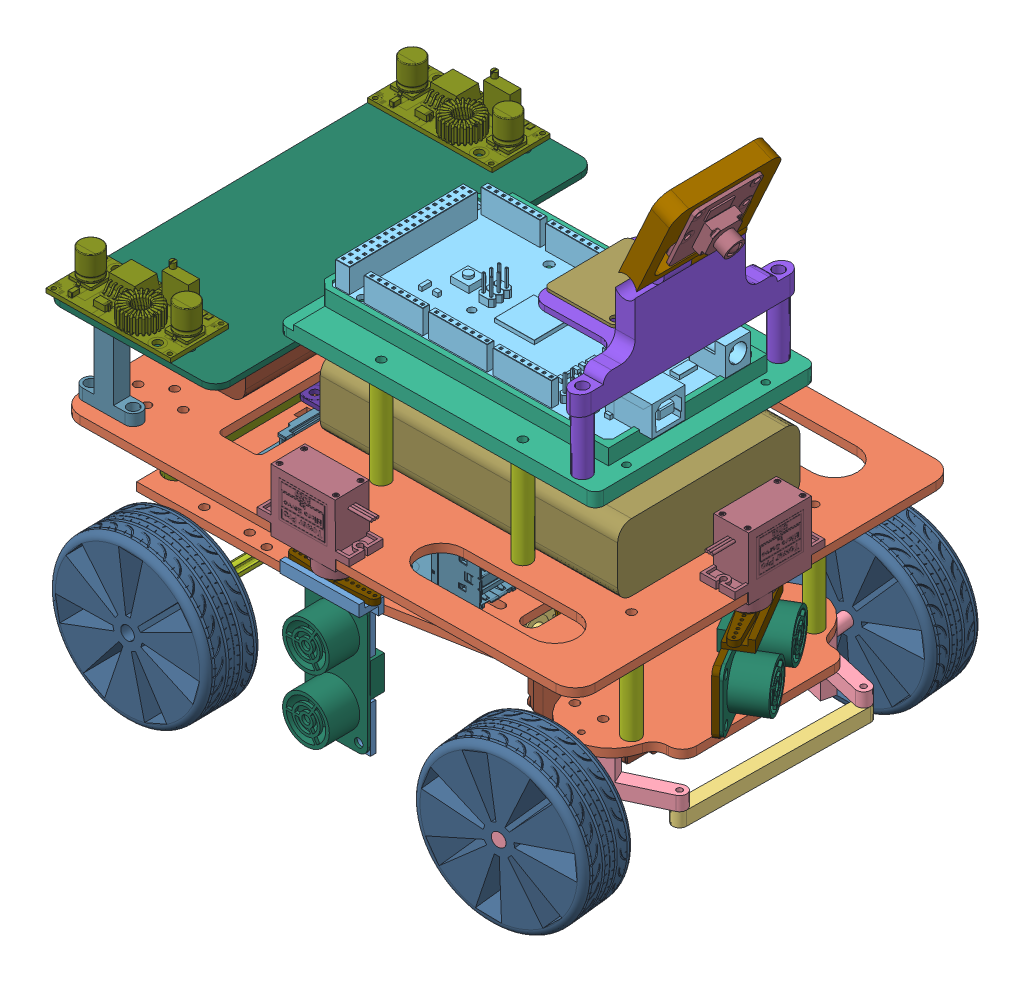
SolidWorks assembly Assem1, configuration Default. Lengths in mm.
Overall size (212.54 214.25 158.19).
63 component instances, 37 part files, 163 mates.
Components (placement in the parent):
- Lego Beam Fram 5x7 (64179)-2: Lego Beam Fram 5x7 (64179) [Default] at (1116.1167 -16.8 401.0707) x (0.999923 0 -0.012414) z (0 -1 0) size (56 40 8.03)
- chassis-2: chassis [Default] at (910.3673 -11.2 583.6389) x (-0.012414 0 -0.999923) z (-0.999923 0 0.012414) size (90 3 182)
- Core-DC-motor-jsumo-1: Core-DC-motor-jsumo [Default] at (985.0615 -28 582.7116) x (-0.012414 0 -0.999923) z (0.999923 0 -0.012414) size (15 12.1 46.7)
- Lego Beam Fram 5x7 (64179)-3: Lego Beam Fram 5x7 (64179) [Default] at (1120.5858 -32 761.0429) x (0.999923 0 -0.012414) z (0 1 0) size (56 40 8.03)
- (8258)_62821a-DkBluishGray v1-1: (8258)_62821a-DkBluishGray v1 [Default] at (938.2162 -28 571.2922) x (0.793634 -0.608316 -0.009853) z (-0.608269 -0.793695 0.007552) size (29.36 24.07 29.36)
- gear1-1: gear1 [Default] at (964.4047 -29.2721 521.6633) x (-0.138574 -0.225747 -0.96428) z (0.963872 -0.254394 -0.078959) size (6.66 13 13.05)
- gear1-2: gear1 [Default] at (885.5141 2.2697 557.1096) x (-0.878105 0.439182 0.189871) z (-0.360358 -0.345987 -0.866276) size (6.66 13 13.05)
- gear1-3: gear1 [Default] at (941.8438 -1.3082 642.1527) x (-0.230121 -0.091434 0.968857) z (-0.106516 0.991961 0.068315) size (6.66 13 13.05)
- 32269 Technic Gear 20 Tooth Double Bevel-1: 32269 Technic Gear 20 Tooth Double Bevel [Default] at (954.4314 -28 583.0919) x (-0.999923 0 0.012414) z (0.012093 0.225803 0.974098) size (7.95 21.33 21.33)
- 44294 Black Technic Axle 7 v1-1: 44294 Black Technic Axle 7 v1 [Default] at (938.3006 -28 578.0917) x (-0.012414 0 -0.999923) z (0.983452 -0.180757 -0.012209) size (56 4.8 4.8)
- 44294 Black Technic Axle 7 v1-2: 44294 Black Technic Axle 7 v1 [Default] at (939.0951 -28 642.0868) x (-0.012414 0 -0.999923) z (0.983452 -0.180757 -0.012209) size (56 4.8 4.8)
- dc holder-1: dc holder [Default] at (989.0612 -25.625 582.6619) x (0.012414 0 0.999923) z (0.999923 0 -0.012414) size (45 10.75 11)
- dc holder2-1: dc holder2 [Default] at (1006.3294 -18.0698 569.9466) x (-0.999923 0 0.012414) z (0.012414 0 0.999923) size (25 22.25 45)
- 56mm Wheel Normal Tread v1-1: 56mm Wheel Normal Tread v1 [Default] at (986.4091 9.1172 655.7005) x (-0.618573 0.78569 0.00768) z (-0.012414 0 -0.999923) size (56 56 20.01)
- 56mm Wheel Normal Tread v1-2: 56mm Wheel Normal Tread v1 [Default] at (952.6765 30.0378 510.108) x (0.967223 -0.253645 -0.012008) z (0.012414 0 0.999923) size (56 56 20.01)
- Tower Pro MG-995, Analog Servo-1: Tower Pro MG-995, Analog Servo [Default] at (1054.3587 -24.1 582.0513) x (0 -1 0) z (0.012414 0 0.999923) size (19.81 47.29 67)
- power bank-1: power bank [Default] at (1067.6573 50.8 613.0128) x (-0.999923 0 0.012414) z (0 -1 0) size (105 66 24)
- servo-1: servo [Default] at (1008.363 45.1 651.1539) x (-0.999923 0 0.012414) z (0.012414 -0.002078 0.999921) size (35.6 29.7 12.5)
- servo-2: servo [Default] at (1006.8105 45.1 526.1036) x (-0.999923 0 0.012414) z (0.012414 -0.002078 0.999921) size (35.6 29.7 12.5)
- Raspberry Pi 4 Model B-1: Raspberry Pi 4 Model B [Default] at (970.8626 -7.4 582.8879) x (0.999923 0 -0.012414) z (0.012414 0 0.999923) size (88.99 19.91 58.4)
- URM09 ultrasonic sensor-1: URM09 ultrasonic sensor [Default] at (910.369 4.65 583.7739) x (-0.012414 0 -0.999923) z (0 1 0) size (47 17.1 22)
- wall-1: wall [Default] at (918.4819 8.2872 592.8181) x (-0.012414 0 -0.999923) z (-0.999923 0 0.012414) size (70 35 8)
- ServoHat for Raspberry-1: ServoHat for Raspberry [Default] at (960.6015 3.9 569.9742) x (-0.999923 0 0.012414) z (-0.012414 0 -0.999923) size (65 18.5 30)
- Servo Medium Horn-1: Servo Medium Horn [Default] at (1002.1364 18.6128 645.0257) x (-0.999923 0 0.012414) z (0.012414 -0.002078 0.999921) size (31.17 4.71 6.86)
- Servo Medium Horn-2: Servo Medium Horn [Default] at (1000.5839 18.6128 519.9753) x (-0.510712 0.0018 -0.85975) z (-0.859752 -0.001039 0.510711) size (31.17 4.71 6.86)
- URM09 ultrasonic sensor-2: URM09 ultrasonic sensor [Default] at (1002.1182 -12.2692 643.5316) x (0.000026 0.999998 0.002078) z (0.999923 0 -0.012414) size (47 17.1 22)
- servotoultra-1: servotoultra [Default] at (987.9963 9.664 633.7986) x (-0.012414 0.002078 -0.999921) z (0.999923 0 -0.012414) size (9 52.1 28)
- layer2-2: layer2 [Default] at (996.8416 23.8 -431.3964) x (-0.999923 0 0.012414) z (-0.012414 0 -0.999923) size (182 3 137.36)
- servotoultra-3: servotoultra [Default] at (997.947 9.6033 537.8067) x (-0.859752 -0.001039 0.510711) z (-0.510712 0.0018 -0.85975) size (9 52.1 28)
- URM09 ultrasonic sensor-4: URM09 ultrasonic sensor [Default] at (999.3537 -12.2736 520.6414) x (0.000026 0.999998 0.002078) z (-0.510712 0.0018 -0.85975) size (47 17.1 22)
- URM09 ultrasonic sensor-5: URM09 ultrasonic sensor [Default] at (1084.9092 1.2406 582.1947) x (0.510712 0 0.859752) z (0 1 0) size (47 17.1 22)
- middle-1: middle [Default] at (1091.7997 -32.7 611.5252) x (-0.012361 0 0.999924) z (-0.999924 0 -0.012361) size (70 5 5)
- side-1: side [Default] at (1092.6031 -14.2 546.5301) x (-0.97527 0 -0.221017) z (-0.221017 0 0.97527) size (41.48 22 36.07)
- side-2: side [Default] at (1091.7997 -36.2 611.5252) x (-0.906304 0 0.422627) z (-0.422627 0 -0.906304) size (41.48 22 36.07)
- 56mm Wheel Normal Tread v1-3: 56mm Wheel Normal Tread v1 [Default] at (1103.2585 26.1421 653.3939) x (-0.850647 0.51747 0.092869) z (-0.108529 0 -0.994093) size (56 56 20.01)
- 56mm Wheel Normal Tread v1-4: 56mm Wheel Normal Tread v1 [Default] at (1045.8916 31.9534 508.3395) x (0.947336 0.304362 -0.099589) z (0.104549 0 0.99452) size (56 56 20.01)
- ArduinoMega-1: ArduinoMega [Default] at (1012.1453 68.451 582.3772) x (0.999923 0 -0.012414) z (0 -1 0) size (107.95 53.42 12.95)
- Arduino Mega Case1-1: Arduino Mega Case1 [Default] at (1015.3496 61.8 581.9138) x (-0.999923 0 0.012414) z (-0.012414 0 -0.999923) size (112.02 10.5 80)
- hexa-1: hexa [Default] at (1040.9219 26.8 546.5191) size (6 35 6)
- hexa-2: hexa [Default] at (1041.8033 26.8 617.5099) size (6 35 6)
- hexa-3: hexa [Default] at (991.8071 26.8 618.1306) size (6 35 6)
- hexa-4: hexa [Default] at (990.9258 26.8 547.1398) size (6 35 6)
- cameraholder-1: cameraholder [Default] at (1055.4272 83.8 580.0213) x (0.012414 0 0.999923) z (-0.999923 0 0.012414) size (79.94 53.8 37.5)
- cameraholder2-1: cameraholder2 [Default] at (1073.1754 128.8363 583.8508) x (0.012414 0 0.999923) z (-0.90993 0.414608 0.011297) size (40 38.8 8)
- DRV8871_module-2: DRV8871_module [Default] at (1041.238 -10.45 567.173) x (-0.012414 0 -0.999923) z (0 1 0) size (20.32 24.13 5.45)
- battery-2: battery [Default] at (925.4133 45.3 592.7888) x (-0.012414 0 -0.999923) z (0 -1 0) size (73 34 18.5)
- bno086-1: bno086 [Default] at (1041.7556 94.8 583.0556) x (-0.999923 0 0.012414) z (0.012414 0 0.999923) size (25.4 1 30.48)
- Pi camera module3-1: Pi camera module3 [Default] at (1075.0098 130.2224 581.5987) x (-0.012414 0 -0.999923) z (0.414576 0.91 -0.005147) size (25 12.5 23.86)
- powerboardholder-1: powerboardholder [Default] at (921.1525 26.8 522.8203) x (0.999923 0 -0.012414) z (0.012414 0 0.999923) size (21 30 6)
- powerboardholder-2: powerboardholder [Default] at (922.659 26.8 644.171) x (0.999923 0 -0.012414) z (0.012414 0 0.999923) size (21 30 6)
- powerboardholder2-1: powerboardholder2 [Default] at (912.0463 56.8 1334.6568) x (0.012414 0 0.999923) z (-0.999923 0 0.012414) size (137.36 2 60)
- XL4005_MODELO_3D_1-3: XL4005_MODELO_3D_1 [Default] at (927.1873 15.55 646.6872) x (0.999923 0 -0.012414) z (0 1 0) size (44.01 21.69 13.13)
- XL4005_MODELO_3D_1-4: XL4005_MODELO_3D_1 [Default] at (925.7428 15.55 530.3361) x (0.999923 0 -0.012414) z (0 1 0) size (44.01 21.69 13.13)
- hexaforraspberry-1: hexaforraspberry [Default] at (990.1653 -11.2 607.1501) size (6 3 6)
- hexaforraspberry-2: hexaforraspberry [Default] at (989.557 -11.2 558.1539) size (6 3 6)
- hexaforraspberry-3: hexaforraspberry [Default] at (931.5615 -11.2 558.8739) size (6 3 6)
- hexaforraspberry-4: hexaforraspberry [Default] at (932.1698 -11.2 607.8701) size (6 3 6)
- hexa-5: hexa [Default] at (1076.9448 -11.2 548.5683) size (6 35 6)
- hexa-6: hexa [Default] at (1077.6773 -11.2 614.5643) size (6 35 6)
- servotoultra - Copy-1: servotoultra - Copy [Default] at (1083.502 9.6531 599.3144) x (-0.859752 0 0.510712) z (-0.510712 0 -0.859752) size (9 26.1 47)
- servo-3: servo [Default] at (1080.1302 45.1256 587.6518) x (-0.012414 0 -0.999923) z (-0.999923 0 0.012414) size (35.6 29.7 12.5)
- Servo Medium Horn-3: Servo Medium Horn [Default] at (1086.2034 18.6256 581.4259) x (0.50278 0 0.864414) z (0.864414 0 -0.50278) size (31.17 4.71 6.86)
- additional-1: additional [Default] at (938.3651 -17.2 583.2913) x (-0.999923 0 0.012414) z (-0.012414 0 -0.999923) size (56 3 40)
Mates (geometry in assembly coordinates):
- Parallel3: parallel anti-aligned: plane of Lego Beam Fram 5x7 (64179)-2 through (910.3673 -17.2 583.6389) normal (0 1 0); plane of chassis-2 through (1048.4263 -14.2 616.9276) normal (0 -1 0)
- Distance2: distance = 21 mm aligned: plane of Lego Beam Fram 5x7 (64179)-2 through (962.115 -20.8 562.9949) normal (-0.012414 0 -0.999923); plane of chassis-2 through (909.8583 -14.2 542.6421) normal (-0.012414 0 -0.999923)
- Coincident8: coincident aligned: plane of Lego Beam Fram 5x7 (64179)-2 through (910.3673 -17.9 583.6389) normal (-0.999923 0 0.012414); plane of chassis-2 through (910.8763 -14.2 624.6357) normal (-0.999923 0 0.012414)
- Distance120: distance = 3 mm anti-aligned: plane of Lego Beam Fram 5x7 (64179)-2 through (910.3673 -17.2 583.6389) normal (0 1 0); plane of chassis-2 through (1048.4263 -14.2 616.9276) normal (0 -1 0)
- Coincident10: coincident anti-aligned: plane of Lego Beam Fram 5x7 (64179)-2 through (918.3667 -24.4 583.5396) normal (0 -1 0); plane of Lego Beam Fram 5x7 (64179)-3 through (918.3667 -24.4 583.5396) normal (0 1 0)
- Coincident11: coincident aligned: plane of Lego Beam Fram 5x7 (64179)-2 through (962.115 -20.8 562.9949) normal (-0.012414 0 -0.999923); plane of Lego Beam Fram 5x7 (64179)-3 through (962.115 -28 562.9949) normal (-0.012414 0 -0.999923)
- Concentric1: concentric aligned: cylinder of Lego Beam Fram 5x7 (64179)-2 through (914.1684 -20.8 567.5905) axis (0 -1 0) radius 2.4; cylinder of Lego Beam Fram 5x7 (64179)-3 through (914.1684 -28 567.5905) axis (0 -1 0) radius 2.4
- Parallel4: parallel anti-aligned: plane of chassis-2 through (1048.4263 -14.2 616.9276) normal (0 -1 0); plane of Core-DC-motor-jsumo-1 through (985.1422 -21.95 589.2111) normal (0 1 0)
- Concentric3: concentric aligned: cylinder of (8258)_62821a-DkBluishGray v1-1 through (938.2584 -28 574.692) axis (0.012414 0 0.999923) radius 2.4; cylinder of gear1-1 through (938.2584 -28 574.692) axis (0.012414 0 0.999923) radius 3.6
- Coincident13: coincident anti-aligned: plane of (8258)_62821a-DkBluishGray v1-1 through (936.3611 -26.54 575.3156) normal (0.012414 0 0.999923); plane of gear1-1 through (936.5286 -34.1597 575.3135) normal (-0.012414 0 -0.999923)
- Coincident15: coincident anti-aligned: plane of (8258)_62821a-DkBluishGray v1-1 through (928.8754 -27.1019 575.4085) normal (0.793634 -0.608316 -0.009853); plane of gear1-2 through (929.5081 -26.4257 584.6168) normal (-0.793634 0.608316 0.009853)
- Concentric5: concentric aligned: cylinder of (8258)_62821a-DkBluishGray v1-1 through (932.0012 -23.1335 582.1702) axis (0.793634 -0.608316 -0.009853) radius 1.2; cylinder of gear1-2 through (932.4774 -23.4985 582.1643) axis (0.793634 -0.608316 -0.009853) radius 3.6
- Coincident16: coincident anti-aligned: plane of (8258)_62821a-DkBluishGray v1-1 through (930.4983 -21.9168 588.9894) normal (-0.012414 0 -0.999923); plane of gear1-3 through (932.085 -28.7973 588.9697) normal (0.012414 0 0.999923)
- Concentric6: concentric anti-aligned: cylinder of (8258)_62821a-DkBluishGray v1-1 through (938.462 -28 591.0907) axis (0.012414 0 0.999923) radius 2.4; cylinder of gear1-3 through (938.4421 -28 589.4908) axis (-0.012414 0 -0.999923) radius 3.6
- Coincident18: coincident anti-aligned: plane of Lego Beam Fram 5x7 (64179)-3 through (914.218 -28 571.5902) normal (0.012414 0 0.999923); plane of (8258)_62821a-DkBluishGray v1-1 through (926.7879 -19.2402 571.4341) normal (-0.012414 0 -0.999923)
- Concentric7: concentric anti-aligned: cylinder of Lego Beam Fram 5x7 (64179)-3 through (938.1665 -28 567.2925) axis (-0.012414 0 -0.999923) radius 2.4; cylinder of (8258)_62821a-DkBluishGray v1-1 through (938.2584 -28 574.692) axis (0.012414 0 0.999923) radius 2.4
- Concentric10: concentric anti-aligned: cylinder of Core-DC-motor-jsumo-1 through (973.8624 -28 582.8506) axis (-0.999923 0 0.012414) radius 1.5; cylinder of 32269 Technic Gear 20 Tooth Double Bevel-1 through (950.4583 -28 583.1412) axis (0.999923 0 -0.012414) radius 1.6
- Concentric11: concentric anti-aligned: cylinder of Core-DC-motor-jsumo-1 through (973.8624 -28 582.8506) axis (-0.999923 0 0.012414) radius 1.5; cylinder of Lego Beam Fram 5x7 (64179)-3 through (910.3673 -28 583.6389) axis (0.999923 0 -0.012414) radius 2.4
- Distance4: distance = 40 mm aligned: plane of 32269 Technic Gear 20 Tooth Double Bevel-1 through (958.3636 -28 583.043) normal (0.999923 0 -0.012414); plane of Lego Beam Fram 5x7 (64179)-3 through (918.3667 -31.6 583.5396) normal (0.999923 0 -0.012414)
- Concentric12: concentric anti-aligned: cylinder of Lego Beam Fram 5x7 (64179)-3 through (938.5638 -28 599.2901) axis (-0.012414 0 -0.999923) radius 2.4; cylinder of 44294 Black Technic Axle 7 v1-1 through (937.6054 -28 522.096) axis (0.012414 0 0.999923) radius 2.4
- Concentric14: concentric anti-aligned: cylinder of Lego Beam Fram 5x7 (64179)-3 through (938.1665 -28 567.2925) axis (-0.012414 0 -0.999923) radius 2.4; cylinder of 44294 Black Technic Axle 7 v1-2 through (938.3999 -28 586.0911) axis (0.012414 0 0.999923) radius 2.4
- Coincident26: coincident aligned: plane of gear1-3 through (938.3999 -28 586.0911) normal (-0.012414 0 -0.999923); plane of 44294 Black Technic Axle 7 v1-2 through (938.3999 -28 586.0911) normal (-0.012414 0 -0.999923)
- Coincident27: coincident aligned: plane of gear1-1 through (938.3006 -28 578.0917) normal (0.012414 0 0.999923); plane of 44294 Black Technic Axle 7 v1-1 through (938.3006 -28 578.0917) normal (0.012414 0 0.999923)
- Coincident29: coincident anti-aligned: plane of Core-DC-motor-jsumo-1 through (985.1422 -21.95 589.2111) normal (0 1 0); plane of dc holder-1 through (1004.9813 -21.95 588.9648) normal (0 -1 0)
- Parallel6: parallel anti-aligned: plane of Core-DC-motor-jsumo-1 through (962.3336 -29.049 580.6029) normal (0 -1 0); plane of 32269 Technic Gear 20 Tooth Double Bevel-1 through (950.4717 -29.1805 584.2211) normal (0 1 0)
- Concentric19: concentric anti-aligned: cylinder of Core-DC-motor-jsumo-1 through (985.0615 -28 582.7116) axis (0.999923 0 -0.012414) radius 7.5; cylinder of dc holder2-1 through (1036.7017 -28 582.0705) axis (-0.999923 0 0.012414) radius 7.75
- Concentric20: concentric anti-aligned: cylinder of Core-DC-motor-jsumo-1 through (985.0615 -28 582.7116) axis (0.999923 0 -0.012414) radius 7.5; cylinder of dc holder2-1 through (1036.7017 -28 582.0705) axis (-0.999923 0 0.012414) radius 7.75
- Concentric21: concentric aligned: cylinder of 44294 Black Technic Axle 7 v1-2 through (938.3999 -28 586.0911) axis (0.012414 0 0.999923) radius 2.4; cylinder of 56mm Wheel Normal Tread v1-1 through (939.0231 -28 636.2854) axis (0.012414 0 0.999923) radius 2.4
- Concentric22: concentric anti-aligned: cylinder of 44294 Black Technic Axle 7 v1-1 through (937.6054 -28 522.096) axis (0.012414 0 0.999923) radius 2.4; cylinder of 56mm Wheel Normal Tread v1-2 through (937.7072 -28 530.2972) axis (-0.012414 0 -0.999923) radius 2.4
- Distance7: distance = 12 mm anti-aligned: plane of 56mm Wheel Normal Tread v1-1 through (939.0231 -28 636.2872) normal (-0.012414 0 -0.999923); plane of chassis-2 through (910.8763 -14.2 624.6357) normal (0.012414 0 0.999923)
- Distance8: distance = 12 mm anti-aligned: plane of 56mm Wheel Normal Tread v1-2 through (937.7072 -28 530.2954) normal (0.012414 0 0.999923); plane of chassis-2 through (909.8583 -14.2 542.6421) normal (-0.012414 0 -0.999923)
- Coincident47: coincident anti-aligned: plane of chassis-2 through (1048.4263 -14.2 616.9276) normal (0 -1 0); plane of Tower Pro MG-995, Analog Servo-1 through (1054.1067 -14.2 561.7528) normal (0 1 0)
- Coincident109: coincident anti-aligned: plane of URM09 ultrasonic sensor-1 through (910.369 4.65 583.7739) normal (0.999923 0 -0.012414); plane of wall-1 through (910.4825 8.2872 592.9174) normal (-0.999923 0 0.012414)
- Coincident124: coincident anti-aligned: plane of Raspberry Pi 4 Model B-1 through (936.4154 -4.1 557.5435) normal (0 1 0); plane of ServoHat for Raspberry-1 through (960.6015 -4.1 569.9742) normal (0 -1 0)
- Coincident126: coincident aligned: plane of Raspberry Pi 4 Model B-1 through (953.3083 -4.1 556.0637) normal (-0.012414 0 -0.999923); plane of ServoHat for Raspberry-1 through (985.9258 -4.1 555.6588) normal (-0.012414 0 -0.999923)
- Coincident127: coincident aligned: plane of Raspberry Pi 4 Model B-1 through (985.9307 -4.1 556.0587) normal (0.999923 0 -0.012414); plane of ServoHat for Raspberry-1 through (985.9258 -4.1 555.6588) normal (0.999923 0 -0.012414)
- Distance61: distance = 144 mm aligned: plane of Tower Pro MG-995, Analog Servo-1 through (1054.3587 -24.1 582.0513) normal (-0.999923 0 0.012414); plane of chassis-2 through (910.8763 -14.2 624.6357) normal (-0.999923 0 0.012414)
- Distance62: distance = 9.5 mm aligned: plane of Tower Pro MG-995, Analog Servo-1 through (1054.6107 -14.2 602.3497) normal (0.012414 0 0.999923); plane of chassis-2 through (1027.7932 -14.2 612.1834) normal (0.012414 0 0.999923)
- Concentric34: concentric aligned: cylinder of servo-1 through (1002.1363 15.4128 645.0191) axis (0.000026 0.999998 0.002078) radius 0.8; circle of Servo Medium Horn-1
- Coincident134: coincident anti-aligned: plane of servo-1 through (1000.6865 18.6128 645.0437) normal (-0.000026 -0.999998 -0.002078); plane of Servo Medium Horn-1 through (1002.1364 18.6128 645.0257) normal (0.000026 0.999998 0.002078)
- Concentric35: concentric aligned: cylinder of servo-2 through (1000.5839 15.4128 519.9687) axis (0.000026 0.999998 0.002078) radius 0.8; cylinder of Servo Medium Horn-2 through (1000.5839 15.8128 519.9695) axis (0.000026 0.999998 0.002078) radius 2.345
- Coincident135: coincident anti-aligned: plane of servo-2 through (999.134 18.6128 519.9933) normal (-0.000026 -0.999998 -0.002078); plane of Servo Medium Horn-2 through (1000.5839 18.6128 519.9753) normal (0.000026 0.999998 0.002078)
- Concentric36: concentric anti-aligned: cylinder of Servo Medium Horn-1 through (1010.3137 16.3278 644.9194) axis (-0.000026 -0.999998 -0.002078) radius 0.515; cylinder of servotoultra-1 through (1010.3136 12.2278 644.9109) axis (0.000026 0.999998 0.002078) radius 1.5
- Concentric41: concentric anti-aligned: cylinder of Servo Medium Horn-1 through (993.959 16.3278 645.1225) axis (-0.000026 -0.999998 -0.002078) radius 0.515; cylinder of servotoultra-1 through (993.9592 12.2278 645.114) axis (0.000026 0.999998 0.002078) radius 1.5
- Coincident138: coincident anti-aligned: plane of Servo Medium Horn-1 through (1002.1363 14.2278 645.0166) normal (-0.000026 -0.999998 -0.002078); plane of servotoultra-1 through (1016.1799 14.2204 648.4125) normal (0.000026 0.999998 0.002078)
- Coincident150: coincident anti-aligned: plane of chassis-2 through (1048.4263 -11.2 616.9276) normal (0 1 0); plane of wall-1 through (910.8018 -11.2 618.6362) normal (0 -1 0)
- Coincident151: coincident anti-aligned: plane of wall-1 through (910.8018 23.8 618.6362) normal (0 1 0); plane of layer2-2 through (996.8416 23.8 -431.3964) normal (0 -1 0)
- Coincident152: coincident anti-aligned: plane of power bank-1 through (1067.6573 26.8 613.0128) normal (0 -1 0); plane of layer2-2 through (996.8416 26.8 -431.3964) normal (0 1 0)
- Distance68: distance = 20 mm aligned: plane of layer2-2 through (1093.2059 26.8 650.0543) normal (0.999923 0 -0.012414); plane of power bank-1 through (1071.9452 26.8 548.6304) normal (0.999923 0 -0.012414)
- Distance70: distance = 35.68 mm aligned: plane of layer2-2 through (1091.5007 26.8 512.7049) normal (-0.012414 0 -0.999923); plane of power bank-1 through (1071.9452 26.8 548.6304) normal (-0.012414 0 -0.999923)
- Coincident167: coincident anti-aligned: plane of servo-2 through (983.9591 26.8 514.0482) normal (0 -1 0); plane of layer2-2 through (996.8416 26.8 -431.3964) normal (0 1 0)
- Coincident172: coincident: line of servo-2 through (1000.5077 22.8256 513.8345) axis (-0.999923 0 0.012414); plane of layer2-2 through (1091.5007 26.8 512.7049) normal (-0.012414 0 -0.999923)
- Distance77: distance = 91 mm: line of assembly; plane of layer2-2 through (1093.2059 26.8 650.0543) normal (0.999923 0 -0.012414)
- Coincident174: coincident anti-aligned: plane of servo-1 through (1008.2098 26.8 638.8168) normal (0 -1 0); plane of layer2-2 through (996.8416 26.8 -431.3964) normal (0 1 0)
- Coincident175: coincident: line of servo-1 through (1002.2129 22.8 651.1839) axis (-0.999923 0 0.012414); plane of layer2-2 through (1093.2059 26.8 650.0543) normal (0.012414 0 0.999923)
- Distance78: distance = 91 mm: line of assembly; plane of layer2-2 through (1093.2059 26.8 650.0543) normal (0.999923 0 -0.012414)
- Parallel60: parallel anti-aligned: plane of chassis-2 through (910.8763 -14.2 624.6357) normal (-0.999923 0 0.012414); plane of servotoultra-1 through (1013.1179 9.2308 643.4398) normal (0.999923 0 -0.012414)
- Coincident183: coincident anti-aligned: plane of URM09 ultrasonic sensor-2 through (1002.1182 -12.2692 643.5316) normal (-0.012414 0.002078 -0.999921); plane of servotoultra-1 through (1016.1165 -35.7691 643.309) normal (0.012414 -0.002078 0.999921)
- Coincident192: coincident anti-aligned: plane of servotoultra-3 through (992.2031 -35.7484 508.5561) normal (0.859752 0.001039 -0.510711); plane of URM09 ultrasonic sensor-4 through (999.3537 -12.2736 520.6414) normal (-0.859752 -0.001039 0.510711)
- Coincident193: coincident aligned: plane of servotoultra-3 through (993.7364 9.2461 511.2289) normal (-0.510712 0.0018 -0.85975); plane of URM09 ultrasonic sensor-4 through (993.7353 -32.6038 511.1419) normal (-0.510712 0.0018 -0.85975)
- Coincident194: coincident aligned: plane of servotoultra-3 through (990.4836 -35.7504 509.5775) normal (-0.000026 -0.999998 -0.002078); plane of URM09 ultrasonic sensor-4 through (1003.3622 -35.7877 527.3416) normal (-0.000026 -0.999998 -0.002078)
- Concentric52: concentric anti-aligned: cylinder of Servo Medium Horn-2 through (1004.7605 16.3131 527.0016) axis (-0.000026 -0.999998 -0.002078) radius 0.515; cylinder of servotoultra-3 through (1004.7604 12.2131 526.9931) axis (0.000026 0.999998 0.002078) radius 1.5
- Concentric53: concentric anti-aligned: cylinder of Servo Medium Horn-2 through (996.4073 16.3425 512.9395) axis (-0.000026 -0.999998 -0.002078) radius 0.515; cylinder of servotoultra-3 through (996.4073 12.2425 512.9313) axis (0.000026 0.999998 0.002078) radius 1.5
- Coincident195: coincident anti-aligned: plane of Servo Medium Horn-2 through (1000.5838 14.2278 519.9662) normal (-0.000026 -0.999998 -0.002078); plane of servotoultra-3 through (996.5032 14.2567 506.1065) normal (0.000026 0.999998 0.002078)
- Angle4: planar angle = 2.094395 rad aligned: plane of chassis-2 through (910.8763 -14.2 624.6357) normal (-0.999923 0 0.012414); plane of servotoultra-3 through (997.947 9.6033 537.8067) normal (0.510712 -0.0018 0.85975)
- Parallel72: parallel anti-aligned: plane of chassis-2 through (1048.4263 -14.2 616.9276) normal (0 -1 0); plane of assembly through (0 0 0) normal (0 1 0)
- Tangent5: tangent: circle of 56mm Wheel Normal Tread v1-2; plane of assembly through (0 0 0) normal (0 1 0)
- Concentric54: concentric aligned: cylinder of chassis-2 through (1066.8462 -11.2 540.6931) axis (0 -1 0) radius 1; cylinder of side-1 through (1066.8462 -14.2 540.6931) axis (0 -1 0) radius 1
- Coincident205: coincident anti-aligned: plane of chassis-2 through (1048.4263 -14.2 616.9276) normal (0 -1 0); plane of side-1 through (1092.6031 -14.2 546.5301) normal (0 1 0)
- Concentric55: concentric anti-aligned: cylinder of chassis-2 through (1067.8642 -11.2 622.6868) axis (0 -1 0) radius 1; cylinder of side-2 through (1067.8642 -36.2 622.6868) axis (0 1 0) radius 1
- Coincident206: coincident anti-aligned: plane of chassis-2 through (1048.4263 -14.2 616.9276) normal (0 -1 0); plane of side-2 through (1091.7997 -14.2 611.5252) normal (0 1 0)
- Concentric56: concentric anti-aligned: cylinder of middle-1 through (1092.6031 -32.701 546.5301) axis (0 1 0) radius 1; cylinder of side-1 through (1092.6031 -14.2 546.5301) axis (0 -1 0) radius 1
- Concentric57: concentric aligned: cylinder of middle-1 through (1091.7997 -32.701 611.5252) axis (0 1 0) radius 1; cylinder of side-2 through (1091.7997 -36.2 611.5252) axis (0 1 0) radius 1
- Coincident207: coincident anti-aligned: plane of middle-1 through (1091.7997 -27.7 611.5252) normal (0 1 0); plane of side-1 through (1077.0637 -27.7 540.4452) normal (0 -1 0)
- Coincident208: coincident anti-aligned: plane of middle-1 through (1091.7997 -27.7 611.5252) normal (0 1 0); plane of side-2 through (1075.7891 -27.7 616.2328) normal (0 -1 0)
- Concentric61: concentric anti-aligned: cylinder of side-2 through (1072.3937 -25.2 656.7635) axis (-0.108529 0 -0.994093) radius 2.4; cylinder of 56mm Wheel Normal Tread v1-3 through (1070.2229 -25.2 636.8798) axis (0.108529 0 0.994093) radius 2.4
- Coincident220: coincident aligned: plane of side-2 through (1072.3937 -25.2 656.7635) normal (0.108529 0 0.994093); plane of 56mm Wheel Normal Tread v1-3 through (1072.3937 -25.2 656.7635) normal (0.108529 0 0.994093)
- Concentric62: concentric anti-aligned: cylinder of side-1 through (1064.0532 -25.2 506.4303) axis (0.104549 0 0.99452) radius 2.4; cylinder of 56mm Wheel Normal Tread v1-4 through (1066.1444 -25.2 526.3225) axis (-0.104549 0 -0.99452) radius 2.4
- Coincident221: coincident aligned: plane of side-1 through (1064.0532 -25.2 506.4303) normal (-0.104549 0 -0.99452); plane of 56mm Wheel Normal Tread v1-4 through (1064.0532 -25.2 506.4303) normal (-0.104549 0 -0.99452)
- Concentric63: concentric aligned: cylinder of ArduinoMega-1 through (973.9927 66.799 607.0209) axis (0 1 0) radius 1.5621; cylinder of Arduino Mega Case1-1 through (973.9927 58.8 607.0209) axis (0 1 0) radius 1.5621
- Concentric64: concentric aligned: cylinder of ArduinoMega-1 through (965.9002 66.799 558.7814) axis (0 1 0) radius 1.5621; cylinder of Arduino Mega Case1-1 through (965.9002 58.8 558.7814) axis (0 1 0) radius 1.5621
- Coincident223: coincident anti-aligned: plane of ArduinoMega-1 through (1062.6099 66.8 555.0406) normal (0 -1 0); plane of Arduino Mega Case1-1 through (1015.3496 66.8 581.9138) normal (0 1 0)
- Distance88: distance = 2 mm aligned: plane of chassis-2 through (1027.0483 -14.2 552.188) normal (-0.012414 0 -0.999923); plane of Raspberry Pi 4 Model B-1 through (928.0183 -6.6 555.4176) normal (-0.012414 0 -0.999923)
- Concentric72: concentric anti-aligned: cylinder of Arduino Mega Case1-1 through (1040.9219 60.7999 546.5191) axis (0 1 0) radius 1.5; cylinder of hexa-1 through (1040.9219 61.8 546.5191) axis (0 -1 0) radius 2
- Concentric73: concentric anti-aligned: cylinder of Arduino Mega Case1-1 through (990.9258 60.7999 547.1398) axis (0 1 0) radius 1.5; cylinder of hexa-4 through (990.9258 61.8 547.1398) axis (0 -1 0) radius 2
- Concentric74: concentric anti-aligned: cylinder of Arduino Mega Case1-1 through (1041.8033 60.7999 617.5099) axis (0 1 0) radius 1.5; cylinder of hexa-2 through (1041.8033 61.8 617.5099) axis (0 -1 0) radius 2
- Concentric75: concentric anti-aligned: cylinder of Arduino Mega Case1-1 through (991.8071 60.7999 618.1306) axis (0 1 0) radius 1.5; cylinder of hexa-3 through (991.8071 61.8 618.1306) axis (0 -1 0) radius 2
- Concentric82: concentric aligned: cylinder of Arduino Mega Case1-1 through (1061.9203 60.7999 546.2585) axis (0 1 0) radius 1.5; cylinder of cameraholder-1 through (1061.9203 63.8 546.2585) axis (0 1 0) radius 2
- Concentric87: concentric anti-aligned: cylinder of layer2-2 through (1040.9219 23.8 546.5191) axis (0 1 0) radius 1.5; cylinder of hexa-1 through (1040.9219 61.8 546.5191) axis (0 -1 0) radius 3
- Concentric89: concentric anti-aligned: cylinder of layer2-2 through (1041.8033 23.8 617.5099) axis (0 1 0) radius 1.5; cylinder of hexa-2 through (1041.8033 61.8 617.5099) axis (0 -1 0) radius 3
- Coincident245: coincident anti-aligned: plane of Arduino Mega Case1-1 through (1015.3496 63.8 581.9138) normal (0 1 0); plane of cameraholder-1 through (1062.8017 63.8 617.253) normal (0 -1 0)
- Concentric92: concentric aligned: cylinder of Arduino Mega Case1-1 through (1062.8017 60.7999 617.253) axis (0 1 0) radius 1.5; cylinder of cameraholder-1 through (1062.8017 63.8 617.253) axis (0 1 0) radius 3
- Coincident246: coincident anti-aligned: plane of layer2-2 through (996.8416 26.8 -431.3964) normal (0 1 0); plane of hexa-1 through (1040.9219 26.8 546.5191) normal (0 -1 0)
- Coincident248: coincident anti-aligned: plane of layer2-2 through (996.8416 26.8 -431.3964) normal (0 1 0); plane of battery-2 through (925.4133 26.8 592.7888) normal (0 -1 0)
- Coincident249: coincident aligned: plane of layer2-2 through (911.2199 26.8 652.3136) normal (-0.999923 0 0.012414); plane of battery-2 through (910.8204 26.8 620.1361) normal (-0.999923 0 0.012414)
- Distance100: distance = 32.18 mm aligned: plane of battery-2 through (943.9116 26.8 546.7196) normal (-0.012414 0 -0.999923); plane of layer2-2 through (1091.5007 26.8 512.7049) normal (-0.012414 0 -0.999923)
- Coincident260: coincident anti-aligned: plane of cameraholder-1 through (1029.1119 93.8 602.17) normal (0 1 0); plane of bno086-1 through (1041.7556 93.8 583.0556) normal (0 -1 0)
- Coincident263: coincident aligned: plane of cameraholder-1 through (1028.841 83.8 580.3514) normal (-0.999923 0 0.012414); plane of bno086-1 through (1029.0527 93.8 597.4004) normal (-0.999923 0 0.012414)
- Distance104: distance = 4.75 mm aligned: plane of cameraholder-1 through (1028.6153 93.8 562.1731) normal (-0.012414 0 -0.999923); plane of bno086-1 through (1054.0723 93.8 566.6074) normal (-0.012414 0 -0.999923)
- Coincident265: coincident anti-aligned: plane of cameraholder2-1 through (1073.1754 128.8363 583.8508) normal (0.90993 -0.414608 -0.011297); plane of Pi camera module3-1 through (1073.9907 130.6867 581.6113) normal (-0.90993 0.414608 0.011297)
- Distance106: distance = 7.5 mm aligned: plane of cameraholder2-1 through (1073.3557 146.7212 561.6177) normal (-0.012414 0 -0.999923); plane of Pi camera module3-1 through (1068.8892 119.8295 569.1737) normal (-0.012414 0 -0.999923)
- Distance105: distance = 2.5 mm aligned: plane of Pi camera module3-1 through (1079.0922 141.5439 594.049) normal (0.414576 0.91 -0.005147); plane of cameraholder2-1 through (1073.3557 146.7212 561.6177) normal (0.414576 0.91 -0.005147)
- Coincident268: coincident anti-aligned: plane of layer2-2 through (996.8416 26.8 -431.3964) normal (0 1 0); plane of powerboardholder-1 through (912.6138 26.8 522.9263) normal (0 -1 0)
- Tangent6: tangent aligned: plane of layer2-2 through (911.2199 26.8 652.3136) normal (-0.999923 0 0.012414); cylinder of powerboardholder-1 through (912.6138 56.8 522.9263) axis (0 -1 0) radius 3
- Coincident270: coincident anti-aligned: plane of layer2-2 through (996.8416 26.8 -431.3964) normal (0 1 0); plane of powerboardholder-2 through (914.1203 26.8 644.277) normal (0 -1 0)
- Tangent9: tangent aligned: plane of layer2-2 through (911.2199 26.8 652.3136) normal (-0.999923 0 0.012414); cylinder of powerboardholder-2 through (914.1203 56.8 644.277) axis (0 -1 0) radius 3
- Coincident273: coincident anti-aligned: plane of powerboardholder-1 through (912.6138 56.8 522.9263) normal (0 1 0); plane of powerboardholder2-1 through (961.154 56.8 646.6933) normal (0 -1 0)
- Distance111: distance = 5 mm aligned: plane of layer2-2 through (911.2199 26.8 652.3136) normal (-0.999923 0 0.012414); plane of powerboardholder2-1 through (906.1582 58.8 647.3761) normal (-0.999923 0 0.012414)
- Coincident286: coincident aligned: plane of URM09 ultrasonic sensor-2 through (994.2682 -35.7691 643.5802) normal (-0.000026 -0.999998 -0.002078); plane of servotoultra-1 through (1016.0917 -35.765 641.3092) normal (-0.000026 -0.999998 -0.002078)
- Coincident287: coincident aligned: plane of URM09 ultrasonic sensor-2 through (1013.1168 -32.6191 643.3528) normal (0.999923 0 -0.012414); plane of servotoultra-1 through (1013.1179 9.2308 643.4398) normal (0.999923 0 -0.012414)
- Coincident291: coincident aligned: plane of layer2-2 through (1091.5007 26.8 512.7049) normal (-0.012414 0 -0.999923); plane of powerboardholder2-1 through (959.5109 58.8 514.3435) normal (-0.012414 0 -0.999923)
- Coincident292: coincident anti-aligned: plane of powerboardholder2-1 through (961.154 58.8 646.6933) normal (0 1 0); plane of XL4005_MODELO_3D_1-4 through (926.6437 58.8 525.2524) normal (0 -1 0)
- Coincident293: coincident anti-aligned: plane of powerboardholder2-1 through (961.154 58.8 646.6933) normal (0 1 0); plane of XL4005_MODELO_3D_1-3 through (928.0882 58.8 641.6034) normal (0 -1 0)
- Coincident294: coincident aligned: plane of powerboardholder2-1 through (961.216 58.8 651.6929) normal (0.012414 0 0.999923); plane of XL4005_MODELO_3D_1-3 through (906.2203 60.3 652.3757) normal (0.012414 0 0.999923)
- Coincident295: coincident aligned: plane of powerboardholder2-1 through (906.1582 58.8 647.3761) normal (-0.999923 0 0.012414); plane of XL4005_MODELO_3D_1-3 through (905.9596 60.3 631.3773) normal (-0.999923 0 0.012414)
- Coincident296: coincident aligned: plane of powerboardholder2-1 through (959.5109 58.8 514.3435) normal (-0.012414 0 -0.999923); plane of XL4005_MODELO_3D_1-4 through (904.5151 60.3 515.0263) normal (-0.012414 0 -0.999923)
- Coincident297: coincident aligned: plane of powerboardholder2-1 through (906.1582 58.8 647.3761) normal (-0.999923 0 0.012414); plane of XL4005_MODELO_3D_1-4 through (904.5151 60.3 515.0263) normal (-0.999923 0 0.012414)
- Coincident298: coincident anti-aligned: plane of chassis-2 through (1048.4263 -11.2 616.9276) normal (0 1 0); plane of hexaforraspberry-3 through (931.5615 -11.2 558.8739) normal (0 -1 0)
- Coincident299: coincident anti-aligned: plane of chassis-2 through (1048.4263 -11.2 616.9276) normal (0 1 0); plane of hexaforraspberry-1 through (990.1653 -11.2 607.1501) normal (0 -1 0)
- Coincident300: coincident anti-aligned: plane of chassis-2 through (1048.4263 -11.2 616.9276) normal (0 1 0); plane of hexaforraspberry-4 through (932.1698 -11.2 607.8701) normal (0 -1 0)
- Coincident301: coincident anti-aligned: plane of chassis-2 through (1048.4263 -11.2 616.9276) normal (0 1 0); plane of hexaforraspberry-2 through (989.557 -11.2 558.1539) normal (0 -1 0)
- Concentric93: concentric anti-aligned: cylinder of Raspberry Pi 4 Model B-1 through (931.5615 -6.6 558.8739) axis (0 1 0) radius 1.35; cylinder of hexaforraspberry-3 through (931.5615 -8.2 558.8739) axis (0 -1 0) radius 2
- Coincident302: coincident anti-aligned: plane of Raspberry Pi 4 Model B-1 through (970.8626 -8.2 582.8879) normal (0 -1 0); plane of hexaforraspberry-3 through (931.5615 -8.2 558.8739) normal (0 1 0)
- Concentric94: concentric anti-aligned: cylinder of Raspberry Pi 4 Model B-1 through (989.557 -6.6 558.1539) axis (0 1 0) radius 1.35; cylinder of hexaforraspberry-2 through (989.557 -8.2 558.1539) axis (0 -1 0) radius 2
- Concentric95: concentric anti-aligned: cylinder of Raspberry Pi 4 Model B-1 through (932.1698 -6.6 607.8701) axis (0 1 0) radius 1.35; cylinder of hexaforraspberry-4 through (932.1698 -8.2 607.8701) axis (0 -1 0) radius 2
- Concentric96: concentric anti-aligned: cylinder of Raspberry Pi 4 Model B-1 through (990.1653 -6.6 607.1501) axis (0 1 0) radius 1.35; cylinder of hexaforraspberry-1 through (990.1653 -8.2 607.1501) axis (0 -1 0) radius 2
- Distance117: distance = 10 mm anti-aligned: plane of Raspberry Pi 4 Model B-1 through (928.0183 -6.6 555.4176) normal (-0.999923 0 0.012414); plane of wall-1 through (918.4819 8.2872 592.8181) normal (0.999923 0 -0.012414)
- Concentric97: concentric aligned: cylinder of chassis-2 through (1077.6773 -11.2 614.5643) axis (0 -1 0) radius 1.5; cylinder of hexa-6 through (1077.6773 23.8 614.5643) axis (0 -1 0) radius 2
- Concentric98: concentric aligned: cylinder of chassis-2 through (1076.9448 -11.2 548.5683) axis (0 -1 0) radius 1.5; cylinder of hexa-5 through (1076.9448 23.8 548.5683) axis (0 -1 0) radius 2
- Coincident304: coincident anti-aligned: plane of chassis-2 through (1048.4263 -11.2 616.9276) normal (0 1 0); plane of hexa-6 through (1077.6773 -11.2 614.5643) normal (0 -1 0)
- Coincident305: coincident anti-aligned: plane of chassis-2 through (1048.4263 -11.2 616.9276) normal (0 1 0); plane of hexa-5 through (1076.9448 -11.2 548.5683) normal (0 -1 0)
- Coincident307: coincident anti-aligned: plane of layer2-2 through (1079.6484 26.801 564.956) normal (0.012414 0 0.999923); plane of servo-3 through (1079.8484 45.1256 564.9535) normal (-0.012414 0 -0.999923)
- Distance118: distance = 11.3 mm aligned: plane of layer2-2 through (1093.2059 26.8 650.0543) normal (0.999923 0 -0.012414); plane of servo-3 through (1081.1301 29.3256 587.6394) normal (0.999923 0 -0.012414)
- Concentric100: concentric aligned: circle of servo-3; circle of Servo Medium Horn-3
- Coincident309: coincident anti-aligned: plane of servo-3 through (1086.1854 18.6256 579.976) normal (0 -1 0); plane of Servo Medium Horn-3 through (1086.2034 18.6256 581.4259) normal (0 1 0)
- Coincident313: coincident: plane of layer2-2 through (996.8416 26.8 -431.3964) normal (0 1 0); line of servo-3 through (1092.4901 26.8 592.3987) axis (-0.012414 0 -0.999923)
- Concentric101: concentric anti-aligned: cylinder of servotoultra - Copy-1 through (1086.2034 12.2406 581.4259) axis (0 1 0) radius 3.43; cylinder of Servo Medium Horn-3 through (1086.2034 14.7756 581.4259) axis (0 -1 0) radius 2.4
- Concentric102: concentric anti-aligned: cylinder of servotoultra - Copy-1 through (1090.3153 12.2406 588.4954) axis (0 1 0) radius 1; cylinder of Servo Medium Horn-3 through (1090.3151 16.3406 588.4951) axis (0 -1 0) radius 0.515
- Coincident314: coincident anti-aligned: plane of servotoultra - Copy-1 through (1082.058 14.2406 567.6046) normal (0 1 0); plane of Servo Medium Horn-3 through (1086.2034 14.2406 581.4259) normal (0 -1 0)
- Coincident315: coincident anti-aligned: plane of URM09 ultrasonic sensor-5 through (1084.9092 1.2406 582.1947) normal (-0.859752 0 0.510712); plane of servotoultra - Copy-1 through (1077.7593 -9.7594 570.1581) normal (0.859752 0 -0.510712)
- Coincident316: coincident aligned: plane of URM09 ultrasonic sensor-5 through (1096.911 9.0906 602.3988) normal (0.510712 0 0.859752); plane of servotoultra - Copy-1 through (1088.3537 9.6531 607.482) normal (0.510712 0 0.859752)
- Coincident317: coincident aligned: plane of URM09 ultrasonic sensor-5 through (1095.3022 -9.7594 599.6906) normal (0 -1 0); plane of servotoultra - Copy-1 through (1076.0398 -9.7594 571.1796) normal (0 -1 0)
- Distance119: distance = 10 mm anti-aligned: plane of 32269 Technic Gear 20 Tooth Double Bevel-1 through (958.3636 -28 583.043) normal (0.999923 0 -0.012414); plane of Core-DC-motor-jsumo-1 through (968.3628 -28 582.9189) normal (-0.999923 0 0.012414)
- Coincident321: coincident aligned: plane of Core-DC-motor-jsumo-1 through (985.1422 -34.05 589.2111) normal (0.012414 0 0.999923); plane of dc holder-1 through (991.1418 -18.2 589.1366) normal (0.012414 0 0.999923)
- Coincident324: coincident aligned: plane of Core-DC-motor-jsumo-1 through (974.0624 -28 582.8481) normal (-0.999923 0 0.012414); plane of dc holder-1 through (974.0624 -25.625 582.8481) normal (-0.999923 0 0.012414)
- Coincident326: coincident aligned: plane of Core-DC-motor-jsumo-1 through (1011.5595 -28 582.3826) normal (0.999923 0 -0.012414); plane of dc holder2-1 through (1011.7147 -21.8763 594.8817) normal (0.999923 0 -0.012414)
- Coincident329: coincident aligned: plane of chassis-2 through (910.8763 -14.2 624.6357) normal (-0.999923 0 0.012414); plane of additional-1 through (910.119 -14.2 563.6404) normal (-0.999923 0 0.012414)
- Coincident330: coincident anti-aligned: plane of chassis-2 through (1048.4263 -14.2 616.9276) normal (0 -1 0); plane of additional-1 through (938.3651 -14.2 583.2913) normal (0 1 0)
- Coincident331: coincident aligned: plane of Lego Beam Fram 5x7 (64179)-3 through (962.115 -28 562.9949) normal (-0.012414 0 -0.999923); plane of additional-1 through (966.1147 -14.2 562.9453) normal (-0.012414 0 -0.999923)
- Angle6: planar angle = 0.523599 rad aligned: plane of servotoultra - Copy-1 through (1083.7775 12.2406 566.5832) normal (0.859752 0 -0.510712); plane of layer2-2 through (1093.2059 26.8 650.0543) normal (0.999923 0 -0.012414)
- Concentric106: concentric anti-aligned: cylinder of URM09 ultrasonic sensor-1 through (910.1164 12.5 563.4255) axis (-0.999923 0 0.012414) radius 1.5; cylinder of wall-1 through (910.1164 12.5 563.4255) axis (0.999923 0 -0.012414) radius 2
- Concentric107: concentric anti-aligned: cylinder of URM09 ultrasonic sensor-1 through (910.6216 -3.2 604.1223) axis (-0.999923 0 0.012414) radius 1.5; cylinder of wall-1 through (910.6216 -3.2 604.1223) axis (0.999923 0 -0.012414) radius 2
- Coincident335: coincident aligned: plane of chassis-2 through (910.8763 -14.2 624.6357) normal (-0.999923 0 0.012414); plane of wall-1 through (910.4825 8.2872 592.9174) normal (-0.999923 0 0.012414)
- Distance122: distance = 16 mm aligned: plane of wall-1 through (910.6776 -6.2 608.637) normal (0.012414 0 0.999923); plane of chassis-2 through (910.8763 -14.2 624.6357) normal (0.012414 0 0.999923)
- Concentric109: concentric anti-aligned: cylinder of cameraholder-1 through (1062.361 113.6011 581.7557) axis (0.012414 0 0.999923) radius 2; cylinder of cameraholder2-1 through (1062.361 113.6011 581.7557) axis (-0.012414 0 -0.999923) radius 2
- Coincident340: coincident aligned: plane of cameraholder-1 through (1058.613 113.8 561.8007) normal (-0.012414 0 -0.999923); plane of cameraholder2-1 through (1073.3557 146.7212 561.6177) normal (-0.012414 0 -0.999923)
- Distance123: distance = 5 mm aligned: plane of powerboardholder-1 through (912.5766 56.8 519.9266) normal (-0.012414 0 -0.999923); plane of powerboardholder2-1 through (959.5109 58.8 514.3435) normal (-0.012414 0 -0.999923)
- Distance124: distance = 5 mm aligned: plane of powerboardholder-2 through (914.1576 56.8 647.2768) normal (0.012414 0 0.999923); plane of powerboardholder2-1 through (961.216 58.8 651.6929) normal (0.012414 0 0.999923)
- Distance126: distance = 27.68 mm aligned: plane of layer2-2 through (1093.2059 26.8 650.0543) normal (0.012414 0 0.999923); plane of chassis-2 through (910.8763 -14.2 624.6357) normal (0.012414 0 0.999923)
- Coincident347: coincident aligned: plane of chassis-2 through (910.8763 -14.2 624.6357) normal (-0.999923 0 0.012414); plane of layer2-2 through (911.2199 26.8 652.3136) normal (-0.999923 0 0.012414)
- Coincident348: coincident anti-aligned: plane of chassis-2 through (1048.4263 -11.2 616.9276) normal (0 1 0); plane of DRV8871_module-2 through (1041.238 -11.2 567.173) normal (0 -1 0)
- Distance127: distance = 16 mm anti-aligned: plane of DRV8871_module-2 through (1029.269 -10.45 574.9822) normal (-0.999923 0 0.012414); plane of Raspberry Pi 4 Model B-1 through (1013.0118 -6.6 554.3624) normal (0.999923 0 -0.012414)
- Distance128: distance = 5 mm aligned: plane of DRV8871_module-2 through (1031.5476 -10.45 557.1325) normal (-0.012414 0 -0.999923); plane of chassis-2 through (1027.0483 -14.2 552.188) normal (-0.012414 0 -0.999923)
